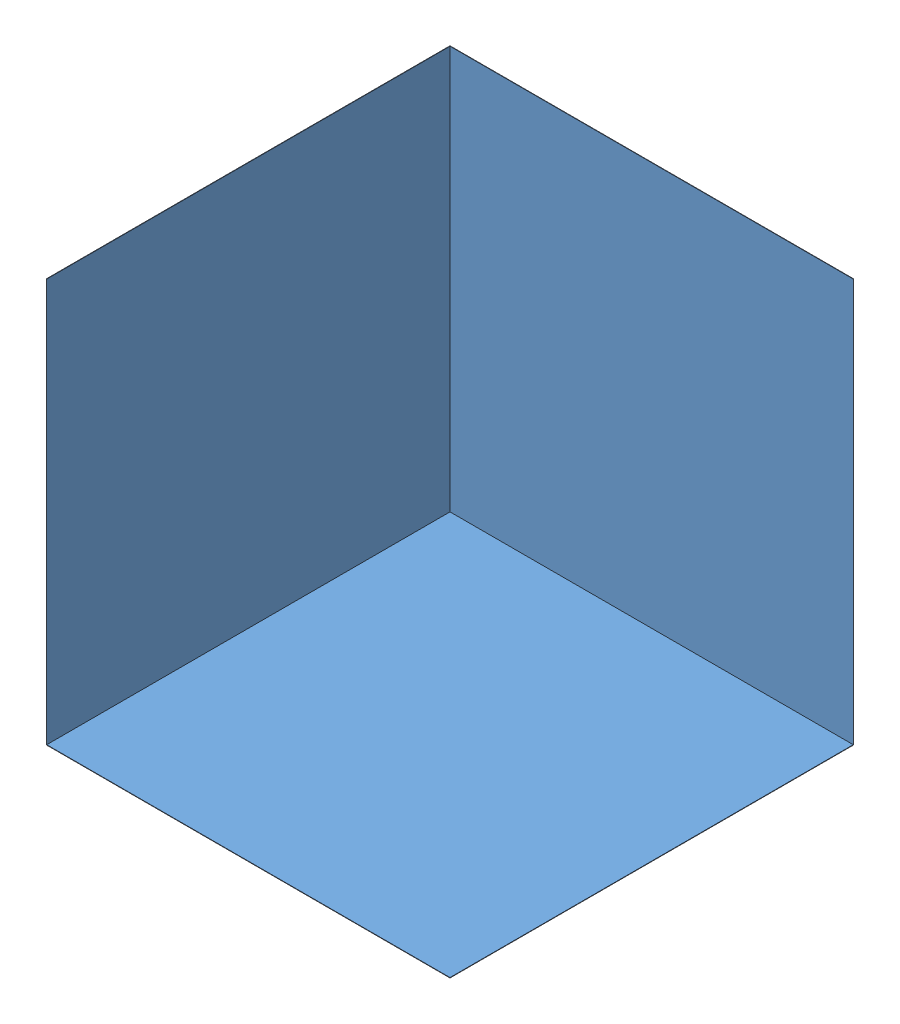
SolidWorks assembly 装配体1, configuration 默认. Lengths in mm.
Overall size (1001 1001 1001).
3 component instances, 1 part files, 6 mates.
Components (placement in the parent):
- 面-1: 面 [默认] at origin size (1000 1 1000)
- 面-2: 面 [默认] at (-501 501 0) x (0 -1 0) z (0 0 1) size (1000 1 1000)
- 面-3: 面 [默认] at (0 501 -501) x (1 0 0) z (0 -1 0) size (1000 1 1000)
Mates (geometry in assembly coordinates):
- 重合1: coincident anti-aligned: line of 面-1 through (-500 1 -500) axis (0 0 1); line of 面-2 through (-500 1 500) axis (0 0 -1)
- 重合2: coincident aligned: plane of 面-1 through (-500 1 500) normal (0 0 1); plane of 面-2 through (-500 1001 500) normal (0 0 1)
- LimitAngle1: limit planar angle = 1.570796 rad aligned: plane of 面-2 through (-500 501 0) normal (1 0 0); plane of 面-1 through (0 1 0) normal (0 1 0)
- 重合4: coincident aligned: plane of 面-1 through (500 1 500) normal (1 0 0); plane of 面-3 through (500 1 -500) normal (1 0 0)
- 重合5: coincident anti-aligned: line of 面-1 through (500 1 -500) axis (-1 0 0); line of 面-3 through (-500 1 -500) axis (1 0 0)
- LimitAngle2: limit planar angle = 1.570796 rad aligned: plane of 面-1 through (0 1 0) normal (0 1 0); plane of 面-3 through (0 501 -500) normal (0 0 1)
